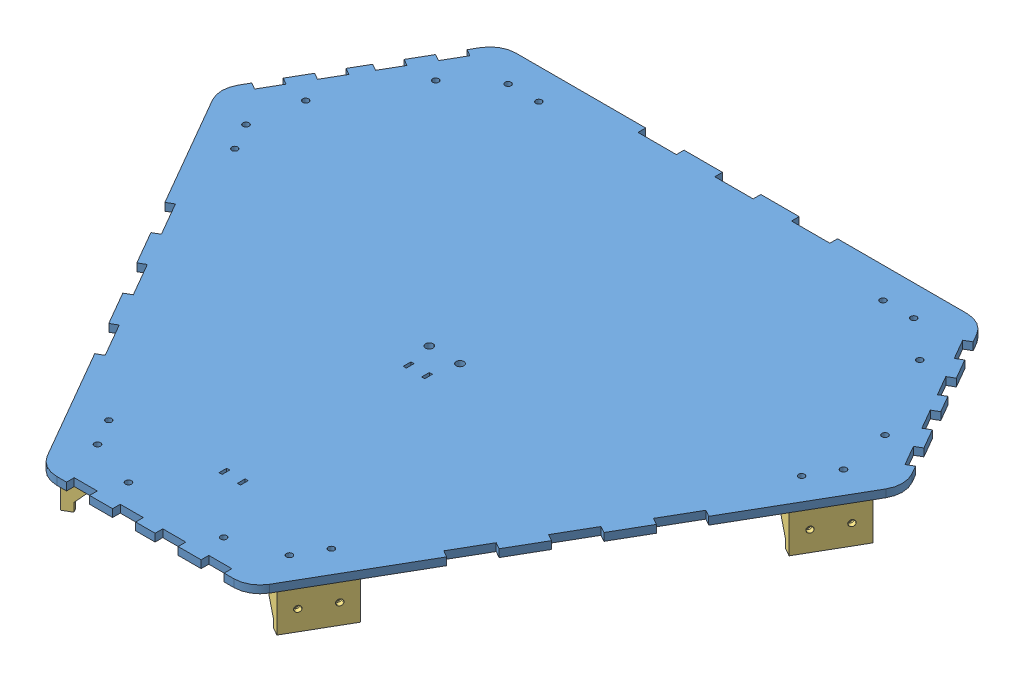
SolidWorks assembly top-assembly, configuration Default. Lengths in mm.
Overall size (443.29 62.64 494.01).
8 component instances, 3 part files, 24 mates.
Components (placement in the parent):
- acrylic-top-1: acrylic-top [Default] x (0 0 1) z (-1 0 0) size (388.46 5 443.29)
- acrylic-nameplate-1: acrylic-nameplate [Default] x (0.866025 0 -0.5) z (0.5 0 0.866025) size (213.61 40 126.21)
- window-bracket-dual-1: window-bracket-dual [Default] at (0 296.5433 -73.4567) x (0.866025 0.5 0) z (0.5 -0.866025 0) size (48.64 28 44.25)
- window-bracket-dual-2: window-bracket-dual [Default] at (-244.2691 296.5433 -73.4567) x (0.866025 0.5 0) z (0.5 -0.866025 0) size (48.64 28 44.25)
- window-bracket-dual-3: window-bracket-dual [Default] at (185.75 296.5433 -174.8149) x (-0.433013 0.5 0.75) z (-0.25 -0.866025 0.433013) size (48.64 28 44.25)
- window-bracket-dual-4: window-bracket-dual [Default] at (63.6154 296.5433 36.7284) x (-0.433013 0.5 0.75) z (-0.25 -0.866025 0.433013) size (48.64 28 44.25)
- window-bracket-dual-5: window-bracket-dual [Default] at (58.5192 296.5433 248.2716) x (-0.433013 0.5 -0.75) z (-0.25 -0.866025 -0.433013) size (48.64 28 44.25)
- window-bracket-dual-6: window-bracket-dual [Default] at (-63.6154 296.5433 36.7284) x (-0.433013 0.5 -0.75) z (-0.25 -0.866025 -0.433013) size (48.64 28 44.25)
Mates (geometry in assembly coordinates):
- Coincident1: coincident aligned: plane of acrylic-top-1 through (0 0 0) normal (0 0 1); plane of assembly through (0 0 0) normal (0 0 1)
- Coincident2: coincident aligned: plane of acrylic-top-1; plane of assembly through (0 0 0) normal (0 1 0)
- Coincident3: coincident anti-aligned: plane of acrylic-top-1 through (0 0 0) normal (-1 0 0); plane of assembly through (0 0 0) normal (1 0 0)
- Coincident4: coincident anti-aligned: plane of acrylic-top-1 through (-146.9606 460 -151.4567) normal (0 -1 0); plane of window-bracket-dual-1 through (0 460 -73.4567) normal (0 1 0)
- Concentric1: concentric aligned: cylinder of acrylic-top-1 through (132.1346 -95 -148.4567) axis (0 1 0) radius 2; cylinder of window-bracket-dual-1 through (132.1346 295.136 -148.4567) axis (0 1 0) radius 2
- Concentric3: concentric aligned: cylinder of acrylic-top-1 through (112.1346 -95 -148.4567) axis (0 1 0) radius 2; cylinder of window-bracket-dual-1 through (112.1346 295.136 -148.4567) axis (0 1 0) radius 2
- Coincident5: coincident anti-aligned: plane of acrylic-top-1 through (-146.9606 460 -151.4567) normal (0 -1 0); plane of window-bracket-dual-2 through (-244.2691 460 -73.4567) normal (0 1 0)
- Concentric4: concentric aligned: cylinder of acrylic-top-1 through (-112.1346 -95 -148.4567) axis (0 1 0) radius 2; cylinder of window-bracket-dual-2 through (-112.1346 295.136 -148.4567) axis (0 1 0) radius 2
- Concentric5: concentric aligned: cylinder of acrylic-top-1 through (-132.1346 -95 -148.4567) axis (0 1 0) radius 2; cylinder of window-bracket-dual-2 through (-132.1346 295.136 -148.4567) axis (0 1 0) radius 2
- Coincident6: coincident anti-aligned: plane of acrylic-top-1 through (-146.9606 460 -151.4567) normal (0 -1 0); plane of window-bracket-dual-3 through (185.75 460 -174.8149) normal (0 1 0)
- Concentric6: concentric aligned: cylinder of acrylic-top-1 through (184.6346 -95 -22.883) axis (0 1 0) radius 2; cylinder of window-bracket-dual-3 through (184.6346 295.136 -22.883) axis (0 1 0) radius 2
- Concentric7: concentric aligned: cylinder of acrylic-top-1 through (194.6346 -95 -40.2035) axis (0 1 0) radius 2; cylinder of window-bracket-dual-3 through (194.6346 295.136 -40.2035) axis (0 1 0) radius 2
- Coincident7: coincident anti-aligned: plane of acrylic-top-1 through (-146.9606 460 -151.4567) normal (0 -1 0); plane of window-bracket-dual-4 through (63.6154 460 36.7284) normal (0 1 0)
- Concentric8: concentric aligned: cylinder of acrylic-top-1 through (62.5 -95 188.6603) axis (0 1 0) radius 2; cylinder of window-bracket-dual-4 through (62.5 295.136 188.6603) axis (0 1 0) radius 2
- Concentric9: concentric aligned: cylinder of acrylic-top-1 through (72.5 -95 171.3397) axis (0 1 0) radius 2; cylinder of window-bracket-dual-4 through (72.5 295.136 171.3397) axis (0 1 0) radius 2
- Coincident8: coincident anti-aligned: plane of acrylic-top-1 through (-146.9606 460 -151.4567) normal (0 -1 0); plane of window-bracket-dual-6 through (-63.6154 460 36.7284) normal (0 1 0)
- Coincident9: coincident aligned: circle of acrylic-top-1; cylinder of window-bracket-dual-6 through (-194.6346 295.136 -40.2035) axis (0 1 0) radius 2
- Concentric10: concentric aligned: cylinder of acrylic-top-1 through (-184.6346 -95 -22.883) axis (0 1 0) radius 2; cylinder of window-bracket-dual-6 through (-184.6346 295.136 -22.883) axis (0 1 0) radius 2
- Coincident10: coincident anti-aligned: plane of acrylic-top-1 through (-146.9606 460 -151.4567) normal (0 -1 0); plane of window-bracket-dual-5 through (58.5192 460 248.2716) normal (0 1 0)
- Concentric11: concentric aligned: cylinder of acrylic-top-1 through (-72.5 -95 171.3397) axis (0 1 0) radius 2; cylinder of window-bracket-dual-5 through (-72.5 295.136 171.3397) axis (0 1 0) radius 2
- Concentric12: concentric aligned: cylinder of acrylic-top-1 through (-62.5 -95 188.6603) axis (0 1 0) radius 2; cylinder of window-bracket-dual-5 through (-62.5 295.136 188.6603) axis (0 1 0) radius 2
- Coincident11: coincident anti-aligned: plane of acrylic-nameplate-1 through (0 0 -163.4567) normal (0 0 1); plane of window-bracket-dual-2 through (-244.2691 370 -163.4567) normal (0 0 -1)
- Concentric13: concentric anti-aligned: cylinder of acrylic-nameplate-1 through (-112.1346 445 -236.3425) axis (0 0 1) radius 2; cylinder of window-bracket-dual-2 through (-112.1346 445 1.4073) axis (0 0 -1) radius 2
- Concentric14: concentric anti-aligned: cylinder of acrylic-nameplate-1 through (112.1346 445 -236.3425) axis (0 0 1) radius 2; cylinder of window-bracket-dual-1 through (112.1346 445 1.4073) axis (0 0 -1) radius 2
